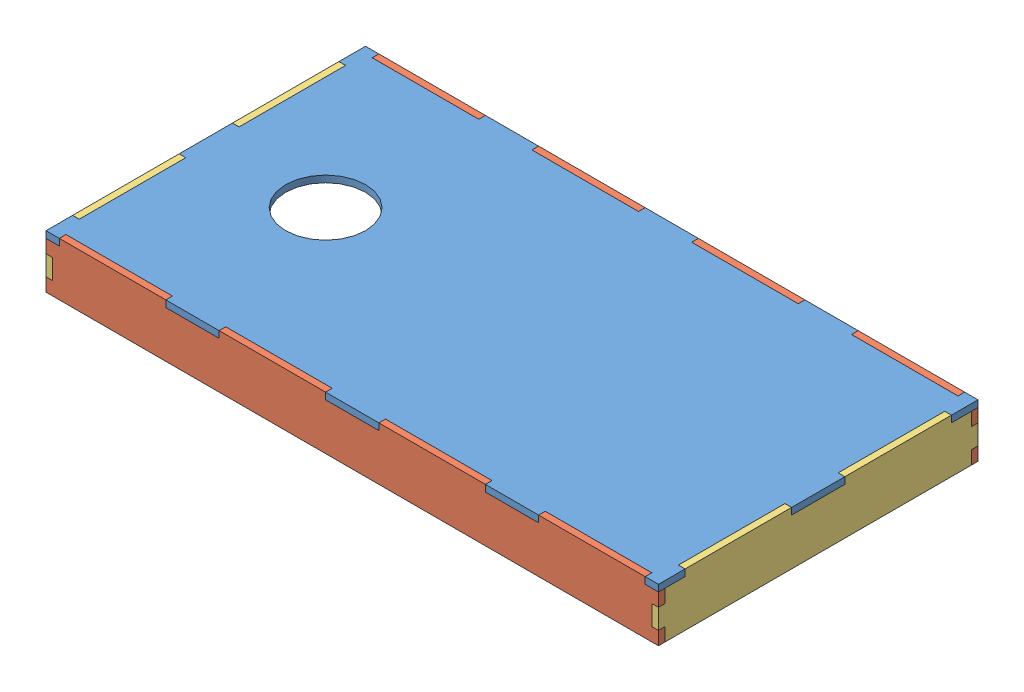
SolidWorks assembly Cornhole Assembly, configuration Default. Lengths in mm.
Overall size (1168.4 101.6 609.6).
5 component instances, 3 part files, 13 mates.
Components (placement in the parent):
- Cornhole Top-1: Cornhole Top [Default] at origin size (1168.4 12.7 609.6)
- Cornhole Side-1: Cornhole Side [Default] at (0 -38.1 292.1) size (1168.4 101.6 12.7)
- Cornhole Side-2: Cornhole Side [Default] at (0 -38.1 -304.8) size (1168.4 101.6 12.7)
- Cornhole Side Top-1: Cornhole Side Top [Default] at (571.5 -38.1 0) size (12.7 101.6 609.6)
- Cornhole Side Top-2: Cornhole Side Top [Default] at (-584.2 -38.1 0) size (12.7 101.6 609.6)
Mates (geometry in assembly coordinates):
- Coincident1: coincident anti-aligned: plane of Cornhole Top-1 through (-558.8 0 292.1) normal (0 0 1); plane of Cornhole Side-1 through (0 -38.1 292.1) normal (0 0 -1)
- Coincident2: coincident anti-aligned: plane of Cornhole Top-1 through (-355.6 0 304.8) normal (-1 0 0); plane of Cornhole Side-1 through (-355.6 12.7 289.052) normal (1 0 0)
- Coincident3: coincident aligned: plane of Cornhole Top-1 through (0 12.7 0) normal (0 1 0); plane of Cornhole Side-1 through (-584.2 12.7 304.8) normal (0 1 0)
- Coincident5: coincident aligned: plane of Cornhole Top-1 through (-584.2 12.7 -304.8) normal (-1 0 0); plane of Cornhole Side-2 through (-584.2 12.7 -292.1) normal (-1 0 0)
- Coincident6: coincident anti-aligned: plane of Cornhole Top-1 through (-558.8 0 -292.1) normal (0 0 -1); plane of Cornhole Side-2 through (0 -38.1 -292.1) normal (0 0 1)
- Coincident7: coincident anti-aligned: plane of Cornhole Top-1 through (-558.8 0 -304.8) normal (1 0 0); plane of Cornhole Side-2 through (-558.8 12.7 -307.848) normal (-1 0 0)
- Coincident8: coincident aligned: plane of Cornhole Top-1 through (0 12.7 0) normal (0 1 0); plane of Cornhole Side-2 through (-584.2 12.7 -292.1) normal (0 1 0)
- Coincident9: coincident anti-aligned: plane of Cornhole Top-1 through (571.5 0 50.8) normal (1 0 0); plane of Cornhole Side Top-1 through (571.5 -38.1 0) normal (-1 0 0)
- Coincident10: coincident aligned: plane of Cornhole Top-1 through (0 12.7 0) normal (0 1 0); plane of Cornhole Side Top-1 through (584.2 12.7 304.8) normal (0 1 0)
- Coincident11: coincident anti-aligned: plane of Cornhole Top-1 through (584.2 0 254) normal (0 0 -1); plane of Cornhole Side Top-1 through (568.452 12.7 254) normal (0 0 1)
- Coincident12: coincident anti-aligned: plane of Cornhole Top-1 through (-571.5 0 -254) normal (-1 0 0); plane of Cornhole Side Top-2 through (-571.5 -38.1 0) normal (1 0 0)
- Coincident13: coincident aligned: plane of Cornhole Side-1 through (0 -38.1 304.8) normal (0 0 1); plane of Cornhole Side Top-2 through (-571.5 12.7 304.8) normal (0 0 1)
- Coincident14: coincident aligned: plane of Cornhole Top-1 through (0 12.7 0) normal (0 1 0); plane of Cornhole Side Top-2 through (-571.5 12.7 304.8) normal (0 1 0)
